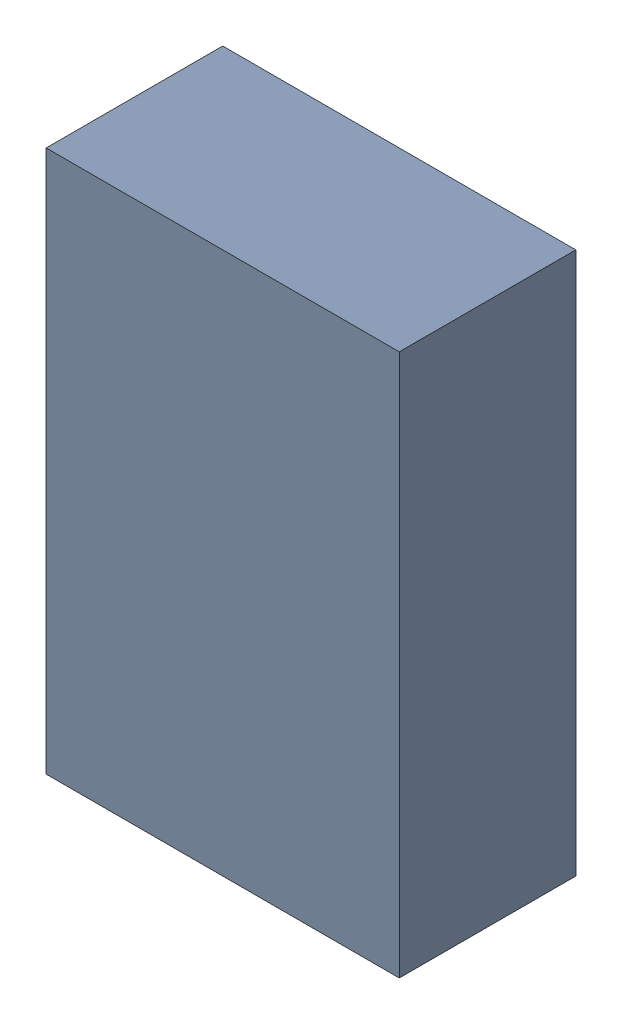
SolidWorks assembly R2-1, configuration Default. Lengths in mm.
Overall size (1.4 2.15 0.7).
2 component instances, 1 part files, 0 mates.
Components (placement in the parent):
- 959208120-1-1: 959208120-1 [Default] at (111.8912 75.852 0) size (1.4 2.15 0.7)
  - Extruded-51-1: Extruded-51 [Default] at origin size (1.4 2.15 0.7)
